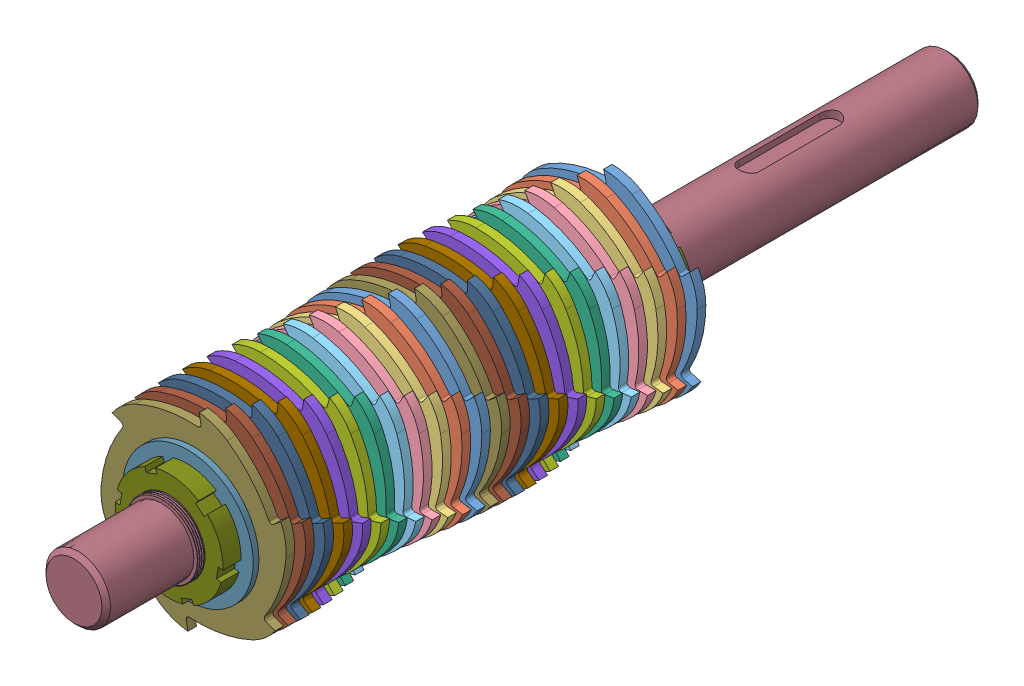
SolidWorks assembly SHRPRO-V1 1120.00-A Shaft 1 assembly, configuration Predeterminado. Lengths in mm.
Overall size (184.22 185.39 610).
75 component instances, 16 part files, 53 mates.
Components (placement in the parent):
- SHRPRO-V1 1120.01-A 6 Teeth blade 1-1: SHRPRO-V1 1120.01-A 6 Teeth blade 1 [6 Teeth Blade 1] at (0 0 -143.75) x (0 0 1) z (-1 0 0) size (6 135.92 126.43)
- SHRPRO-V1 1120.02-A 6 Teeth blade 2-1: SHRPRO-V1 1120.02-A 6 Teeth blade 2 [6 Teeth Blade 2] at (0 0 -131.25) x (0 0 1) z (-0.422618 -0.906308 0) size (6 135.92 126.43)
- SHRPRO-V1 1120.03-A 6 Teeth blade 3-1: SHRPRO-V1 1120.03-A 6 Teeth blade 3 [6 Teeth Blade 3] at (0 0 -118.75) x (0 0 1) z (-0.34202 -0.939693 0) size (6 135.92 126.43)
- SHRPRO-V1 1120.04-A 6 Teeth blade 4-1: SHRPRO-V1 1120.04-A 6 Teeth blade 4 [6 Teeth Blade 4] at (0 0 -106.25) x (0 0 1) z (-0.258819 -0.965926 0) size (6 135.92 126.43)
- SHRPRO-V1 1120.05-A 6 Teeth blade 5-1: SHRPRO-V1 1120.05-A 6 Teeth blade 5 [6 Teeth Blade 5] at (0 0 -93.75) x (0 0 1) z (0.766044 -0.642788 0) size (6 135.92 126.43)
- SHRPRO-V1 1120.06-A 6 Teeth blade 6-1: SHRPRO-V1 1120.06-A 6 Teeth blade 6 [6 Teeth Blade 6] at (0 0 -81.25) x (0 0 1) z (-0.087156 -0.996195 0) size (6 135.92 126.43)
- SHRPRO-V1 1120.07-A 6 Teeth blade 7-1: SHRPRO-V1 1120.07-A 6 Teeth blade 7 [6 Teeth Blade 7] at (0 0 -68.75) x (0 0 1) z (0 -1 0) size (6 135.92 126.43)
- SHRPRO-V1 1120.08-A 6 Teeth blade 8-1: SHRPRO-V1 1120.08-A 6 Teeth blade 8 [6 Teeth Blade 8] at (0 0 -56.25) x (0 0 1) z (0.906308 -0.422618 0) size (6 135.92 126.43)
- SHRPRO-V1 1120.09-A 6 Teeth blade 9-1: SHRPRO-V1 1120.09-A 6 Teeth blade 9 [6 Teeth Blade 9] at (0 0 -43.75) x (0 0 1) z (0.173648 -0.984808 0) size (6 135.92 126.43)
- SHRPRO-V1 1120.10-A 6 Teeth blade 10-1: SHRPRO-V1 1120.10-A 6 Teeth blade 10 [6 Teeth Blade 10] at (0 0 -31.25) x (0 0 1) z (0.258819 -0.965926 0) size (6 135.92 126.43)
- SHRPRO-V1 1120.11-A 6 Teeth blade 11-1: SHRPRO-V1 1120.11-A 6 Teeth blade 11 [6 Teeth Blade 11] at (0 0 -18.75) x (0 0 1) z (0.34202 -0.939693 0) size (6 135.92 126.43)
- SHRPRO-V1 1120.12-A 6 Teeth blade 12-1: SHRPRO-V1 1120.12-A 6 Teeth blade 12 [6 Teeth Blade 12] at (0 0 -6.25) x (0 0 1) z (-0.573576 -0.819152 0) size (6 135.92 126.43)
- SHRPRO-V1 1120.13-A Shaft 1-1: SHRPRO-V1 1120.13-A Shaft 1 [Predeterminado] at origin size (57.74 51.65 610)
- SHRPRO-V1 1120.14-A Spacer 4mm-1: SHRPRO-V1 1120.14-A Spacer 4mm [Défaut] at (0 0 -140.75) x (0.866025 0.5 0) z (0 0 1) size (91 91 4)
- SHRPRO-V1 1120.15-A Spacer 2,5mm-1: SHRPRO-V1 1120.15-A Spacer 2,5mm [Défaut] at (0 0 -136.75) x (0.866025 0.5 0) z (0 0 1) size (91 91 2.5)
- SHRPRO-V1 1120.14-A Spacer 4mm-26: SHRPRO-V1 1120.14-A Spacer 4mm [Défaut] at (0 0 146.75) x (0.866025 0.5 0) z (0 0 1) size (91 91 4)
- SHRPRO-V1 1120.14-A Spacer 4mm-27: SHRPRO-V1 1120.14-A Spacer 4mm [Défaut] at (0 0 -150.75) x (-0.866025 -0.5 0) z (0 0 1) size (91 91 4)
- SHRPRO-V1 DIN 1804 M50x1,5 Slotted round nut-1: SHRPRO-V1 DIN 1804 M50x1,5 Slotted round nut [Default] at (0 0 -163.75) x (-0.954264 -0.298966 0) z (-0.298966 0.954264 0) size (75 13 74.57)
- SHRPRO-V1 DIN 1804 M50x1,5 Slotted round nut-2: SHRPRO-V1 DIN 1804 M50x1,5 Slotted round nut [Default] at (0 0 163.75) x (0.158934 0.987289 0) z (-0.987289 0.158934 0) size (75 13 74.57)
- SHRPRO-V1 1120.15-A Spacer 2,5mm-2: SHRPRO-V1 1120.15-A Spacer 2,5mm [Défaut] at (0 0 -124.25) x (0.866025 0.5 0) z (0 0 1) size (91 91 2.5)
- SHRPRO-V1 1120.15-A Spacer 2,5mm-3: SHRPRO-V1 1120.15-A Spacer 2,5mm [Défaut] at (0 0 -111.75) x (0.866025 0.5 0) z (0 0 1) size (91 91 2.5)
- SHRPRO-V1 1120.15-A Spacer 2,5mm-4: SHRPRO-V1 1120.15-A Spacer 2,5mm [Défaut] at (0 0 -99.25) x (0.866025 0.5 0) z (0 0 1) size (91 91 2.5)
- SHRPRO-V1 1120.14-A Spacer 4mm-4: SHRPRO-V1 1120.14-A Spacer 4mm [Défaut] at (0 0 -128.25) x (0.866025 0.5 0) z (0 0 1) size (91 91 4)
- SHRPRO-V1 1120.14-A Spacer 4mm-5: SHRPRO-V1 1120.14-A Spacer 4mm [Défaut] at (0 0 -115.75) x (0.866025 0.5 0) z (0 0 1) size (91 91 4)
- SHRPRO-V1 1120.14-A Spacer 4mm-6: SHRPRO-V1 1120.14-A Spacer 4mm [Défaut] at (0 0 -103.25) x (0.866025 0.5 0) z (0 0 1) size (91 91 4)
- SHRPRO-V1 1120.14-A Spacer 4mm-7: SHRPRO-V1 1120.14-A Spacer 4mm [Défaut] at (0 0 -90.75) x (0.866025 0.5 0) z (0 0 1) size (91 91 4)
- SHRPRO-V1 1120.14-A Spacer 4mm-8: SHRPRO-V1 1120.14-A Spacer 4mm [Défaut] at (0 0 -78.25) x (0.866025 0.5 0) z (0 0 1) size (91 91 4)
- SHRPRO-V1 1120.14-A Spacer 4mm-9: SHRPRO-V1 1120.14-A Spacer 4mm [Défaut] at (0 0 -65.75) x (0.866025 0.5 0) z (0 0 1) size (91 91 4)
- SHRPRO-V1 1120.14-A Spacer 4mm-10: SHRPRO-V1 1120.14-A Spacer 4mm [Défaut] at (0 0 -53.25) x (0.866025 0.5 0) z (0 0 1) size (91 91 4)
- SHRPRO-V1 1120.14-A Spacer 4mm-11: SHRPRO-V1 1120.14-A Spacer 4mm [Défaut] at (0 0 -40.75) x (0.866025 0.5 0) z (0 0 1) size (91 91 4)
- SHRPRO-V1 1120.14-A Spacer 4mm-12: SHRPRO-V1 1120.14-A Spacer 4mm [Défaut] at (0 0 -28.25) x (0.866025 0.5 0) z (0 0 1) size (91 91 4)
- SHRPRO-V1 1120.14-A Spacer 4mm-13: SHRPRO-V1 1120.14-A Spacer 4mm [Défaut] at (0 0 -15.75) x (0.866025 0.5 0) z (0 0 1) size (91 91 4)
- SHRPRO-V1 1120.14-A Spacer 4mm-14: SHRPRO-V1 1120.14-A Spacer 4mm [Défaut] at (0 0 -3.25) x (0.866025 0.5 0) z (0 0 1) size (91 91 4)
- SHRPRO-V1 1120.14-A Spacer 4mm-15: SHRPRO-V1 1120.14-A Spacer 4mm [Défaut] at (0 0 9.25) x (0.866025 0.5 0) z (0 0 1) size (91 91 4)
- SHRPRO-V1 1120.14-A Spacer 4mm-16: SHRPRO-V1 1120.14-A Spacer 4mm [Défaut] at (0 0 21.75) x (0.866025 0.5 0) z (0 0 1) size (91 91 4)
- SHRPRO-V1 1120.14-A Spacer 4mm-17: SHRPRO-V1 1120.14-A Spacer 4mm [Défaut] at (0 0 34.25) x (0.866025 0.5 0) z (0 0 1) size (91 91 4)
- SHRPRO-V1 1120.14-A Spacer 4mm-18: SHRPRO-V1 1120.14-A Spacer 4mm [Défaut] at (0 0 46.75) x (0.866025 0.5 0) z (0 0 1) size (91 91 4)
- SHRPRO-V1 1120.14-A Spacer 4mm-19: SHRPRO-V1 1120.14-A Spacer 4mm [Défaut] at (0 0 59.25) x (0.866025 0.5 0) z (0 0 1) size (91 91 4)
- SHRPRO-V1 1120.14-A Spacer 4mm-20: SHRPRO-V1 1120.14-A Spacer 4mm [Défaut] at (0 0 71.75) x (0.866025 0.5 0) z (0 0 1) size (91 91 4)
- SHRPRO-V1 1120.14-A Spacer 4mm-21: SHRPRO-V1 1120.14-A Spacer 4mm [Défaut] at (0 0 84.25) x (0.866025 0.5 0) z (0 0 1) size (91 91 4)
- SHRPRO-V1 1120.14-A Spacer 4mm-22: SHRPRO-V1 1120.14-A Spacer 4mm [Défaut] at (0 0 96.75) x (0.866025 0.5 0) z (0 0 1) size (91 91 4)
- SHRPRO-V1 1120.14-A Spacer 4mm-23: SHRPRO-V1 1120.14-A Spacer 4mm [Défaut] at (0 0 109.25) x (0.866025 0.5 0) z (0 0 1) size (91 91 4)
- SHRPRO-V1 1120.14-A Spacer 4mm-24: SHRPRO-V1 1120.14-A Spacer 4mm [Défaut] at (0 0 121.75) x (0.866025 0.5 0) z (0 0 1) size (91 91 4)
- SHRPRO-V1 1120.14-A Spacer 4mm-25: SHRPRO-V1 1120.14-A Spacer 4mm [Défaut] at (0 0 134.25) x (0.866025 0.5 0) z (0 0 1) size (91 91 4)
- SHRPRO-V1 1120.15-A Spacer 2,5mm-5: SHRPRO-V1 1120.15-A Spacer 2,5mm [Défaut] at (0 0 -86.75) x (0.866025 0.5 0) z (0 0 1) size (91 91 2.5)
- SHRPRO-V1 1120.15-A Spacer 2,5mm-6: SHRPRO-V1 1120.15-A Spacer 2,5mm [Défaut] at (0 0 -74.25) x (0.866025 0.5 0) z (0 0 1) size (91 91 2.5)
- SHRPRO-V1 1120.15-A Spacer 2,5mm-7: SHRPRO-V1 1120.15-A Spacer 2,5mm [Défaut] at (0 0 -61.75) x (0.866025 0.5 0) z (0 0 1) size (91 91 2.5)
- SHRPRO-V1 1120.15-A Spacer 2,5mm-8: SHRPRO-V1 1120.15-A Spacer 2,5mm [Défaut] at (0 0 -49.25) x (0.866025 0.5 0) z (0 0 1) size (91 91 2.5)
- SHRPRO-V1 1120.15-A Spacer 2,5mm-9: SHRPRO-V1 1120.15-A Spacer 2,5mm [Défaut] at (0 0 -36.75) x (0.866025 0.5 0) z (0 0 1) size (91 91 2.5)
- SHRPRO-V1 1120.15-A Spacer 2,5mm-10: SHRPRO-V1 1120.15-A Spacer 2,5mm [Défaut] at (0 0 -24.25) x (0.866025 0.5 0) z (0 0 1) size (91 91 2.5)
- SHRPRO-V1 1120.15-A Spacer 2,5mm-11: SHRPRO-V1 1120.15-A Spacer 2,5mm [Défaut] at (0 0 -11.75) x (0.866025 0.5 0) z (0 0 1) size (91 91 2.5)
- SHRPRO-V1 1120.15-A Spacer 2,5mm-12: SHRPRO-V1 1120.15-A Spacer 2,5mm [Défaut] at (0 0 0.75) x (0.866025 0.5 0) z (0 0 1) size (91 91 2.5)
- SHRPRO-V1 1120.15-A Spacer 2,5mm-13: SHRPRO-V1 1120.15-A Spacer 2,5mm [Défaut] at (0 0 13.25) x (0.866025 0.5 0) z (0 0 1) size (91 91 2.5)
- SHRPRO-V1 1120.15-A Spacer 2,5mm-14: SHRPRO-V1 1120.15-A Spacer 2,5mm [Défaut] at (0 0 25.75) x (0.866025 0.5 0) z (0 0 1) size (91 91 2.5)
- SHRPRO-V1 1120.15-A Spacer 2,5mm-15: SHRPRO-V1 1120.15-A Spacer 2,5mm [Défaut] at (0 0 38.25) x (0.866025 0.5 0) z (0 0 1) size (91 91 2.5)
- SHRPRO-V1 1120.15-A Spacer 2,5mm-16: SHRPRO-V1 1120.15-A Spacer 2,5mm [Défaut] at (0 0 50.75) x (0.866025 0.5 0) z (0 0 1) size (91 91 2.5)
- SHRPRO-V1 1120.15-A Spacer 2,5mm-17: SHRPRO-V1 1120.15-A Spacer 2,5mm [Défaut] at (0 0 63.25) x (0.866025 0.5 0) z (0 0 1) size (91 91 2.5)
- SHRPRO-V1 1120.15-A Spacer 2,5mm-18: SHRPRO-V1 1120.15-A Spacer 2,5mm [Défaut] at (0 0 75.75) x (0.866025 0.5 0) z (0 0 1) size (91 91 2.5)
- SHRPRO-V1 1120.15-A Spacer 2,5mm-19: SHRPRO-V1 1120.15-A Spacer 2,5mm [Défaut] at (0 0 88.25) x (0.866025 0.5 0) z (0 0 1) size (91 91 2.5)
- SHRPRO-V1 1120.15-A Spacer 2,5mm-20: SHRPRO-V1 1120.15-A Spacer 2,5mm [Défaut] at (0 0 100.75) x (0.866025 0.5 0) z (0 0 1) size (91 91 2.5)
- SHRPRO-V1 1120.15-A Spacer 2,5mm-21: SHRPRO-V1 1120.15-A Spacer 2,5mm [Défaut] at (0 0 113.25) x (0.866025 0.5 0) z (0 0 1) size (91 91 2.5)
- SHRPRO-V1 1120.15-A Spacer 2,5mm-22: SHRPRO-V1 1120.15-A Spacer 2,5mm [Défaut] at (0 0 125.75) x (0.866025 0.5 0) z (0 0 1) size (91 91 2.5)
- SHRPRO-V1 1120.15-A Spacer 2,5mm-23: SHRPRO-V1 1120.15-A Spacer 2,5mm [Défaut] at (0 0 138.25) x (0.866025 0.5 0) z (0 0 1) size (91 91 2.5)
- SHRPRO-V1 1120.02-A 6 Teeth blade 2-2: SHRPRO-V1 1120.02-A 6 Teeth blade 2 [6 Teeth Blade 2] at (0 0 18.75) x (0 0 1) z (-0.422618 -0.906308 0) size (6 135.92 126.43)
- SHRPRO-V1 1120.11-A 6 Teeth blade 11-2: SHRPRO-V1 1120.11-A 6 Teeth blade 11 [6 Teeth Blade 11] at (0 0 131.25) x (0 0 1) z (0.34202 -0.939693 0) size (6 135.92 126.43)
- SHRPRO-V1 1120.10-A 6 Teeth blade 10-2: SHRPRO-V1 1120.10-A 6 Teeth blade 10 [6 Teeth Blade 10] at (0 0 118.75) x (0 0 1) z (0.258819 -0.965926 0) size (6 135.92 126.43)
- SHRPRO-V1 1120.12-A 6 Teeth blade 12-2: SHRPRO-V1 1120.12-A 6 Teeth blade 12 [6 Teeth Blade 12] at (0 0 143.75) x (0 0 1) z (-0.573576 -0.819152 0) size (6 135.92 126.43)
- SHRPRO-V1 1120.09-A 6 Teeth blade 9-2: SHRPRO-V1 1120.09-A 6 Teeth blade 9 [6 Teeth Blade 9] at (0 0 106.25) x (0 0 1) z (0.173648 -0.984808 0) size (6 135.92 126.43)
- SHRPRO-V1 1120.06-A 6 Teeth blade 6-2: SHRPRO-V1 1120.06-A 6 Teeth blade 6 [6 Teeth Blade 6] at (0 0 68.75) x (0 0 1) z (-0.087156 -0.996195 0) size (6 135.92 126.43)
- SHRPRO-V1 1120.08-A 6 Teeth blade 8-2: SHRPRO-V1 1120.08-A 6 Teeth blade 8 [6 Teeth Blade 8] at (0 0 93.75) x (0 0 1) z (0.906308 -0.422618 0) size (6 135.92 126.43)
- SHRPRO-V1 1120.05-A 6 Teeth blade 5-2: SHRPRO-V1 1120.05-A 6 Teeth blade 5 [6 Teeth Blade 5] at (0 0 56.25) x (0 0 1) z (0.766044 -0.642788 0) size (6 135.92 126.43)
- SHRPRO-V1 1120.04-A 6 Teeth blade 4-2: SHRPRO-V1 1120.04-A 6 Teeth blade 4 [6 Teeth Blade 4] at (0 0 43.75) x (0 0 1) z (-0.258819 -0.965926 0) size (6 135.92 126.43)
- SHRPRO-V1 1120.07-A 6 Teeth blade 7-2: SHRPRO-V1 1120.07-A 6 Teeth blade 7 [6 Teeth Blade 7] at (0 0 81.25) x (0 0 1) z (0 -1 0) size (6 135.92 126.43)
- SHRPRO-V1 1120.03-A 6 Teeth blade 3-2: SHRPRO-V1 1120.03-A 6 Teeth blade 3 [6 Teeth Blade 3] at (0 0 31.25) x (0 0 1) z (-0.34202 -0.939693 0) size (6 135.92 126.43)
- SHRPRO-V1 1120.01-A 6 Teeth blade 1-2: SHRPRO-V1 1120.01-A 6 Teeth blade 1 [6 Teeth Blade 1] at (0 0 6.25) x (0 0 1) z (-1 0 0) size (6 135.92 126.43)
Mates (geometry in assembly coordinates):
- Coincident14: coincident: line of SHRPRO-V1 1120.01-A 6 Teeth blade 1-1 through (0 0 -149.25) axis (0 0 1); line of SHRPRO-V1 1120.13-A Shaft 1-1 through (0 0 165) axis (0 0 -1)
- Coincident16: coincident: line of SHRPRO-V1 1120.14-A Spacer 4mm-1 through (0 0 -134.45) axis (0 0 -1); line of SHRPRO-V1 1120.13-A Shaft 1-1 through (0 0 165) axis (0 0 -1)
- Coincident17: parallel: plane of SHRPRO-V1 1120.13-A Shaft 1-1 through (28.8675 0 150) normal (0.866025 0.5 0); plane of SHRPRO-V1 1120.14-A Spacer 4mm-1 through (28.9252 0 -136.75) normal (-0.866025 -0.5 0)
- Parallel39: parallel: plane of SHRPRO-V1 1120.13-A Shaft 1-1 through (14.4338 25 150) normal (0 1 0); plane of SHRPRO-V1 1120.01-A 6 Teeth blade 1-1 through (14.4626 25.05 -140.75) normal (0 -1 0)
- Coincident106: coincident: line of SHRPRO-V1 1120.13-A Shaft 1-1 through (0 0 165) axis (0 0 -1); line of SHRPRO-V1 1120.15-A Spacer 2,5mm-1 through (0 0 -130.45) axis (0 0 -1)
- Parallel42: parallel: plane of SHRPRO-V1 1120.13-A Shaft 1-1 through (14.4338 -25 150) normal (0.866025 -0.5 0); plane of SHRPRO-V1 1120.15-A Spacer 2,5mm-1 through (14.4626 -25.05 -134.25) normal (-0.866025 0.5 0)
- Concentric106: concentric: cylinder of SHRPRO-V1 1120.13-A Shaft 1-1 through (0 0 265.4923) axis (0 0 1) radius 22.5; cylinder of SHRPRO-V1 DIN 1804 M50x1,5 Slotted round nut-1 through (0 0 -150.75) axis (0 0 1) radius 24.25
- Concentric108: concentric: cylinder of SHRPRO-V1 1120.13-A Shaft 1-1 through (0 0 265.4923) axis (0 0 1) radius 22.5; cylinder of SHRPRO-V1 DIN 1804 M50x1,5 Slotted round nut-2 through (0 0 150.75) axis (0 0 -1) radius 24.25
- Coincident274: coincident: line of SHRPRO-V1 1120.13-A Shaft 1-1 through (0 0 165) axis (0 0 -1); line of SHRPRO-V1 1120.14-A Spacer 4mm-26 through (0 0 153.05) axis (0 0 -1)
- Coincident275: coincident: line of SHRPRO-V1 1120.13-A Shaft 1-1 through (0 0 165) axis (0 0 -1); line of SHRPRO-V1 1120.14-A Spacer 4mm-27 through (0 0 -144.45) axis (0 0 -1)
- Coincident92: coincident: plane of SHRPRO-V1 1120.14-A Spacer 4mm-1 through (0 0 -140.75) normal (0 0 -1); plane of SHRPRO-V1 1120.01-A 6 Teeth blade 1-1 through (0 0 -140.75) normal (0 0 1)
- Coincident279: coincident: plane of SHRPRO-V1 1120.01-A 6 Teeth blade 1-1 through (0 0 -146.75) normal (0 0 -1); plane of SHRPRO-V1 1120.14-A Spacer 4mm-27 through (0 0 -146.75) normal (0 0 1)
- Coincident108: coincident: plane of SHRPRO-V1 1120.14-A Spacer 4mm-1 through (0 0 -136.75) normal (0 0 1); plane of SHRPRO-V1 1120.15-A Spacer 2,5mm-1 through (0 0 -136.75) normal (0 0 -1)
- Parallel45: parallel: plane of SHRPRO-V1 1120.13-A Shaft 1-1 through (-14.4338 25 150) normal (-0.866025 0.5 0); plane of SHRPRO-V1 1120.14-A Spacer 4mm-27 through (14.4626 -25.05 -146.75) normal (-0.866025 0.5 0)
- Parallel46: parallel: plane of SHRPRO-V1 1120.13-A Shaft 1-1 through (14.4338 25 150) normal (0 1 0); plane of SHRPRO-V1 1120.02-A 6 Teeth blade 2-1 through (14.4626 25.05 -128.25) normal (0 -1 0)
- Parallel47: parallel: plane of SHRPRO-V1 1120.13-A Shaft 1-1 through (14.4338 25 150) normal (0 1 0); plane of SHRPRO-V1 1120.03-A 6 Teeth blade 3-1 through (14.4626 25.05 -115.75) normal (0 -1 0)
- Coincident291: coincident: line of SHRPRO-V1 1120.13-A Shaft 1-1 through (0 0 165) axis (0 0 -1); line of SHRPRO-V1 1120.02-A 6 Teeth blade 2-1 through (0 0 -136.75) axis (0 0 1)
- Coincident292: coincident: line of SHRPRO-V1 1120.13-A Shaft 1-1 through (0 0 165) axis (0 0 -1); line of SHRPRO-V1 1120.03-A 6 Teeth blade 3-1 through (0 0 -124.25) axis (0 0 1)
- Parallel49: parallel: plane of SHRPRO-V1 1120.13-A Shaft 1-1 through (14.4338 25 150) normal (0 1 0); plane of SHRPRO-V1 1120.04-A 6 Teeth blade 4-1 through (-14.4626 -25.05 -103.25) normal (0 1 0)
- Parallel50: parallel: plane of SHRPRO-V1 1120.13-A Shaft 1-1 through (14.4338 25 150) normal (0 1 0); plane of SHRPRO-V1 1120.05-A 6 Teeth blade 5-1 through (-14.4626 -25.05 -90.75) normal (0 1 0)
- Parallel51: parallel: plane of SHRPRO-V1 1120.13-A Shaft 1-1 through (14.4338 25 150) normal (0 1 0); plane of SHRPRO-V1 1120.06-A 6 Teeth blade 6-1 through (-14.4626 -25.05 -78.25) normal (0 1 0)
- Parallel52: parallel: plane of SHRPRO-V1 1120.13-A Shaft 1-1 through (14.4338 25 150) normal (0 1 0); plane of SHRPRO-V1 1120.07-A 6 Teeth blade 7-1 through (-14.4626 -25.05 -65.75) normal (0 1 0)
- Coincident293: coincident: line of SHRPRO-V1 1120.13-A Shaft 1-1 through (0 0 165) axis (0 0 -1); line of SHRPRO-V1 1120.04-A 6 Teeth blade 4-1 through (0 0 -111.75) axis (0 0 1)
- Coincident294: coincident: line of SHRPRO-V1 1120.13-A Shaft 1-1 through (0 0 165) axis (0 0 -1); line of SHRPRO-V1 1120.05-A 6 Teeth blade 5-1 through (0 0 -99.25) axis (0 0 1)
- Coincident295: coincident: line of SHRPRO-V1 1120.13-A Shaft 1-1 through (0 0 165) axis (0 0 -1); line of SHRPRO-V1 1120.06-A 6 Teeth blade 6-1 through (0 0 -86.75) axis (0 0 1)
- Coincident296: coincident: line of SHRPRO-V1 1120.13-A Shaft 1-1 through (0 0 165) axis (0 0 -1); line of SHRPRO-V1 1120.07-A 6 Teeth blade 7-1 through (0 0 -74.25) axis (0 0 1)
- Parallel53: parallel: plane of SHRPRO-V1 1120.13-A Shaft 1-1 through (14.4338 25 150) normal (0 1 0); plane of SHRPRO-V1 1120.08-A 6 Teeth blade 8-1 through (-14.4626 -25.05 -53.25) normal (0 1 0)
- Parallel54: parallel: plane of SHRPRO-V1 1120.13-A Shaft 1-1 through (14.4338 25 150) normal (0 1 0); plane of SHRPRO-V1 1120.09-A 6 Teeth blade 9-1 through (14.4626 25.05 -40.75) normal (0 -1 0)
- Parallel55: parallel: plane of SHRPRO-V1 1120.13-A Shaft 1-1 through (14.4338 25 150) normal (0 1 0); plane of SHRPRO-V1 1120.10-A 6 Teeth blade 10-1 through (-14.4626 -25.05 -28.25) normal (0 1 0)
- Parallel56: parallel: plane of SHRPRO-V1 1120.13-A Shaft 1-1 through (14.4338 25 150) normal (0 1 0); plane of SHRPRO-V1 1120.11-A 6 Teeth blade 11-1 through (-14.4626 -25.05 -15.75) normal (0 1 0)
- Coincident297: coincident: line of SHRPRO-V1 1120.13-A Shaft 1-1 through (0 0 165) axis (0 0 -1); line of SHRPRO-V1 1120.08-A 6 Teeth blade 8-1 through (0 0 -61.75) axis (0 0 1)
- Coincident298: coincident: line of SHRPRO-V1 1120.13-A Shaft 1-1 through (0 0 165) axis (0 0 -1); line of SHRPRO-V1 1120.09-A 6 Teeth blade 9-1 through (0 0 -49.25) axis (0 0 1)
- Coincident299: coincident: line of SHRPRO-V1 1120.13-A Shaft 1-1 through (0 0 165) axis (0 0 -1); line of SHRPRO-V1 1120.10-A 6 Teeth blade 10-1 through (0 0 -36.75) axis (0 0 1)
- Coincident300: coincident: line of SHRPRO-V1 1120.13-A Shaft 1-1 through (0 0 165) axis (0 0 -1); line of SHRPRO-V1 1120.11-A 6 Teeth blade 11-1 through (0 0 -24.25) axis (0 0 1)
- Distance3: distance = 6.5 mm: plane of SHRPRO-V1 1120.01-A 6 Teeth blade 1-1 through (0 0 -140.75) normal (0 0 1); plane of SHRPRO-V1 1120.02-A 6 Teeth blade 2-1 through (0 0 -134.25) normal (0 0 -1)
- Distance4: distance = 6.5 mm: plane of SHRPRO-V1 1120.03-A 6 Teeth blade 3-1 through (0 0 -121.75) normal (0 0 -1); plane of SHRPRO-V1 1120.02-A 6 Teeth blade 2-1 through (0 0 -128.25) normal (0 0 1)
- Distance5: distance = 6.5 mm: plane of SHRPRO-V1 1120.03-A 6 Teeth blade 3-1 through (0 0 -115.75) normal (0 0 1); plane of SHRPRO-V1 1120.04-A 6 Teeth blade 4-1 through (0 0 -109.25) normal (0 0 -1)
- Distance6: distance = 6.5 mm: plane of SHRPRO-V1 1120.05-A 6 Teeth blade 5-1 through (0 0 -96.75) normal (0 0 -1); plane of SHRPRO-V1 1120.04-A 6 Teeth blade 4-1 through (0 0 -103.25) normal (0 0 1)
- Distance7: distance = 6.5 mm: plane of SHRPRO-V1 1120.05-A 6 Teeth blade 5-1 through (0 0 -90.75) normal (0 0 1); plane of SHRPRO-V1 1120.06-A 6 Teeth blade 6-1 through (0 0 -84.25) normal (0 0 -1)
- Distance8: distance = 6.5 mm: plane of SHRPRO-V1 1120.07-A 6 Teeth blade 7-1 through (0 0 -71.75) normal (0 0 -1); plane of SHRPRO-V1 1120.06-A 6 Teeth blade 6-1 through (0 0 -78.25) normal (0 0 1)
- Distance9: distance = 6.5 mm: plane of SHRPRO-V1 1120.07-A 6 Teeth blade 7-1 through (0 0 -65.75) normal (0 0 1); plane of SHRPRO-V1 1120.08-A 6 Teeth blade 8-1 through (0 0 -59.25) normal (0 0 -1)
- Distance10: distance = 6.5 mm: plane of SHRPRO-V1 1120.09-A 6 Teeth blade 9-1 through (0 0 -46.75) normal (0 0 -1); plane of SHRPRO-V1 1120.08-A 6 Teeth blade 8-1 through (0 0 -53.25) normal (0 0 1)
- Distance11: distance = 6.5 mm: plane of SHRPRO-V1 1120.09-A 6 Teeth blade 9-1 through (0 0 -40.75) normal (0 0 1); plane of SHRPRO-V1 1120.10-A 6 Teeth blade 10-1 through (0 0 -34.25) normal (0 0 -1)
- Distance12: distance = 6.5 mm: plane of SHRPRO-V1 1120.11-A 6 Teeth blade 11-1 through (0 0 -21.75) normal (0 0 -1); plane of SHRPRO-V1 1120.10-A 6 Teeth blade 10-1 through (0 0 -28.25) normal (0 0 1)
- Parallel57: parallel: plane of SHRPRO-V1 1120.13-A Shaft 1-1 through (14.4338 25 150) normal (0 1 0); plane of SHRPRO-V1 1120.12-A 6 Teeth blade 12-1 through (-14.4626 -25.05 -3.25) normal (0 1 0)
- Coincident311: coincident: line of SHRPRO-V1 1120.13-A Shaft 1-1 through (0 0 165) axis (0 0 -1); line of SHRPRO-V1 1120.12-A 6 Teeth blade 12-1 through (0 0 -11.75) axis (0 0 1)
- Distance13: distance = 6.5 mm: plane of SHRPRO-V1 1120.11-A 6 Teeth blade 11-1 through (0 0 -15.75) normal (0 0 1); plane of SHRPRO-V1 1120.12-A 6 Teeth blade 12-1 through (0 0 -9.25) normal (0 0 -1)
- Coincident312: coincident: plane of SHRPRO-V1 1120.14-A Spacer 4mm-26 through (0 0 146.75) normal (0 0 -1); plane of SHRPRO-V1 1120.12-A 6 Teeth blade 12-2 through (0 0 146.75) normal (0 0 1)
- Parallel58: parallel: plane of SHRPRO-V1 1120.13-A Shaft 1-1 through (-14.4338 25 150) normal (-0.866025 0.5 0); plane of SHRPRO-V1 1120.14-A Spacer 4mm-26 through (-14.4626 25.05 150.75) normal (0.866025 -0.5 0)
- Width1: width: plane of SHRPRO-V1 1120.13-A Shaft 1-1 through (0 0 150) normal (0 0 1); plane of SHRPRO-V1 1120.13-A Shaft 1-1 through (0 0 -150) normal (0 0 -1); plane of SHRPRO-V1 1120.14-A Spacer 4mm-27 through (0 0 -150.75) normal (0 0 -1); plane of SHRPRO-V1 1120.14-A Spacer 4mm-26 through (0 0 150.75) normal (0 0 1)
- Coincident313: coincident: plane of SHRPRO-V1 1120.14-A Spacer 4mm-26 through (0 0 150.75) normal (0 0 1); plane of SHRPRO-V1 DIN 1804 M50x1,5 Slotted round nut-2 through (0 0 150.75) normal (0 0 -1)
- Coincident314: coincident: plane of SHRPRO-V1 1120.14-A Spacer 4mm-27 through (0 0 -150.75) normal (0 0 -1); plane of SHRPRO-V1 DIN 1804 M50x1,5 Slotted round nut-1 through (0 0 -150.75) normal (0 0 1)
- Coordinate2: coordinate: point of SHRPRO-V1 1120.13-A Shaft 1-1; point of assembly
